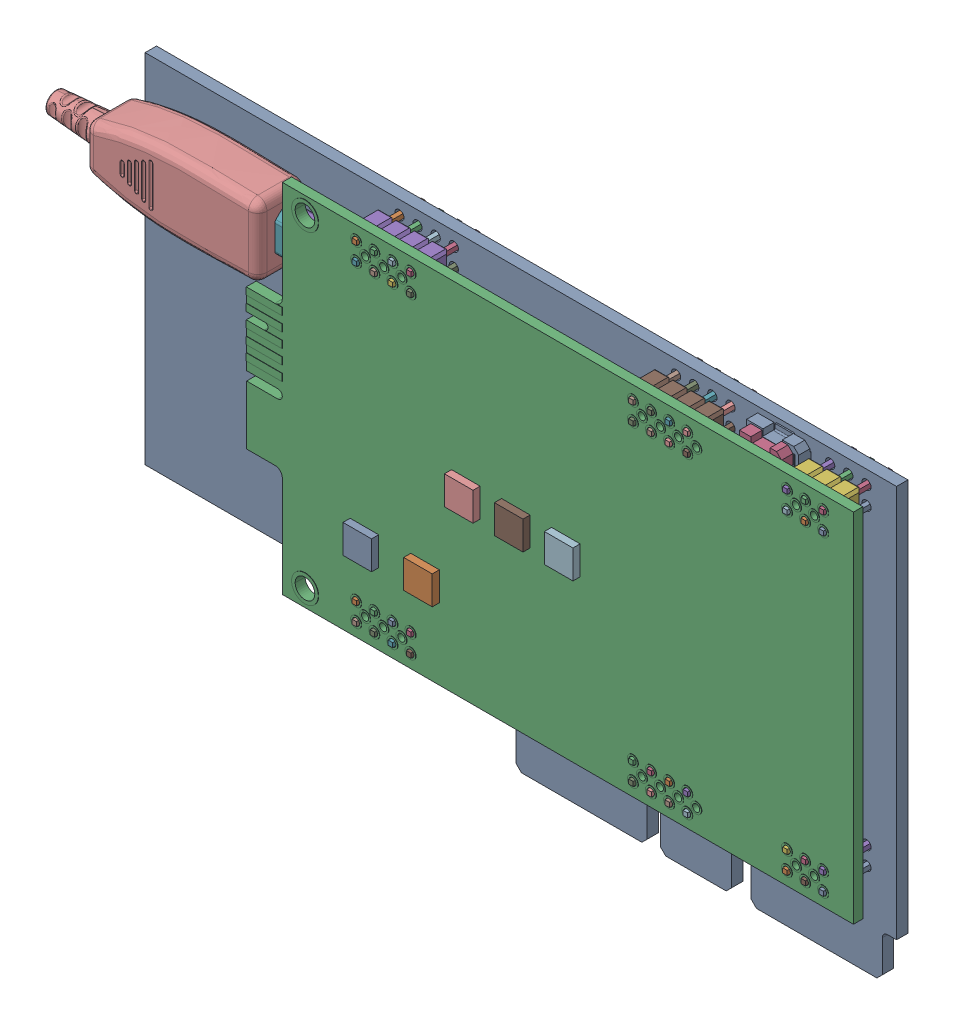
SolidWorks assembly HYDRA_VMM3_CARD_V2(2), configuration Default. Lengths in mm.
Overall size (114.42 61 10.4).
23 component instances, 8 part files, 0 mates.
Components (placement in the parent):
- FX10A-140S14-SV--3DModel-STEP-1-1: FX10A-140S14-SV--3DModel-STEP-1 [Default] at (124.568 -76.306 2.55) x (-1 0 0) z (0 1 0) size (7.3 3.8 49.1)
  - FX10A-140S14-SV--3DModel-STEP-1-0-1: FX10A-140S14-SV--3DModel-STEP-1-0 [Default] at origin size (7.3 3.8 49.1)
- VMM3Hybrid_Reworked-1: VMM3Hybrid_Reworked [Default] at (142.318 -82.856 7.65) x (-1 0 0) z (0 0 -1) size (114.42 50 10.4)
  - VMM3Hybrid_Reworked-1-1: VMM3Hybrid_Reworked-1 [Default] at origin size (114.42 50 10.4)
- R_0603_1608Metric-1: R_0603_1608Metric [Default] at (66.26 -74.8425 -0.05) x (0 1 0) z (0 0 -1) size (1.6 0.8 0.45)
  - R_0603_1608Metric-2-1: R_0603_1608Metric-2 [Default] at origin size (1.6 0.8 0.45)
- R_0603_1608Metric-2: R_0603_1608Metric [Default] at (66.26 -56.3375 -0.05) x (0 -1 0) z (0 0 -1) size (1.6 0.8 0.45)
  - R_0603_1608Metric-2-1: R_0603_1608Metric-2 [Default] at origin size (1.6 0.8 0.45)
- LED_0603_1608Metric-1: LED_0603_1608Metric [Default] at (64.67 -56.36 -0.05) x (0 -1 0) z (0 0 -1) size (1.6 0.8 1.1)
  - LED_0603_1608Metric-3-1: LED_0603_1608Metric-3 [Default] at origin size (1.6 0.8 1.1)
- 20449-001E-03-1: 20449-001E-03 [Default] at (92.3 -36.78 -0.05) x (0 1 0) z (-1 0 0) size (2.01 0.61 2.01)
  - 20449-001E-03-4-1: 20449-001E-03-4 [Default] at origin size (2.01 0.61 2.01)
- TMP104YFFR--3DModel-STEP-56544-1: TMP104YFFR--3DModel-STEP-56544 [Default] at (95.206 -58.0935 -0.05) x (0 -1 0) z (1 0 0) size (0.76 0.62 0.96)
  - TMP104YFFR-1: TMP104YFFR [Default] at origin size (0.76 0.62 0.96)
- Fuse_0603_1608Metric-1: Fuse_0603_1608Metric [Default] at (72.85 -65.31 -0.05) x (-0.707107 0.707107 0) z (0 0 -1) size (1.6 0.8 0.45)
  - Fuse_0603_1608Metric-5-1: Fuse_0603_1608Metric-5 [Default] at origin size (1.6 0.8 0.45)
- Fuse_0603_1608Metric-2: Fuse_0603_1608Metric [Default] at (67.45 -69.02 -0.05) x (-0.707107 0.707107 0) z (0 0 -1) size (1.6 0.8 0.45)
  - Fuse_0603_1608Metric-5-1: Fuse_0603_1608Metric-5 [Default] at origin size (1.6 0.8 0.45)
- LED_0603_1608Metric-2: LED_0603_1608Metric [Default] at (64.67 -74.82 -0.05) x (0 1 0) z (0 0 -1) size (1.6 0.8 1.1)
  - LED_0603_1608Metric-3-1: LED_0603_1608Metric-3 [Default] at origin size (1.6 0.8 1.1)
- 20449-001E-03-2: 20449-001E-03 [Default] at (99.3 -36.78 -0.05) x (0 1 0) z (-1 0 0) size (2.01 0.61 2.01)
  - 20449-001E-03-4-1: 20449-001E-03-4 [Default] at origin size (2.01 0.61 2.01)
- HYDRA_VMM3_CARD_V2_PCB-1: HYDRA_VMM3_CARD_V2_PCB [Default] at origin size (105.25 61 1.6)
